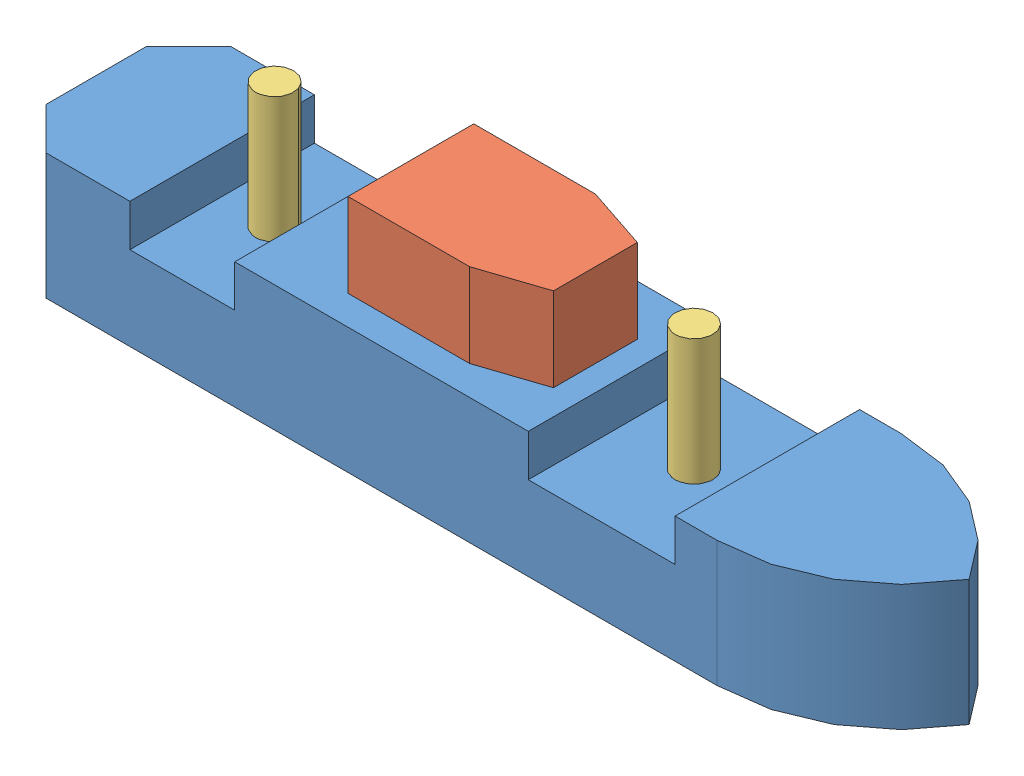
SolidWorks assembly CARGO SHIP, configuration start. Lengths in mm.
Overall size (208.11 50 44).
4 component instances, 3 part files, 5 mates.
Components (placement in the parent):
- BASE-1: BASE [Default] at origin
- WHEEL ROOM-1: WHEEL ROOM [Default] at (-91 30 -37) x (-1 0 0) z (0 0 -1)
- DOWELL-1: DOWELL [Default] at (-167.5 0 -22)
- DOWELL-2: DOWELL [Default] at (-67.5 0 -22)
Mates (geometry in assembly coordinates):
- Distance1: distance = 20 mm aligned: plane of BASE-1 through (-155 20 -44) normal (-1 0 0); plane of WHEEL ROOM-1 through (-135 50 -37) normal (-1 0 0)
- Coincident3: coincident anti-aligned: plane of BASE-1 through (0 30 0) normal (0 1 0); plane of WHEEL ROOM-1 through (-135 30 -7) normal (0 -1 0)
- Width1: width: plane of WHEEL ROOM-1 through (-106 50 -7) normal (0 0 1); plane of WHEEL ROOM-1 through (-106 50 -37) normal (0 0 -1); plane of BASE-1 through (0 30 -44) normal (0 0 -1); plane of BASE-1 through (0 30 0) normal (0 0 1)
- Coincident5: coincident aligned: circle of BASE-1; circle of DOWELL-2
- Coincident6: coincident aligned: circle of BASE-1; circle of DOWELL-1
